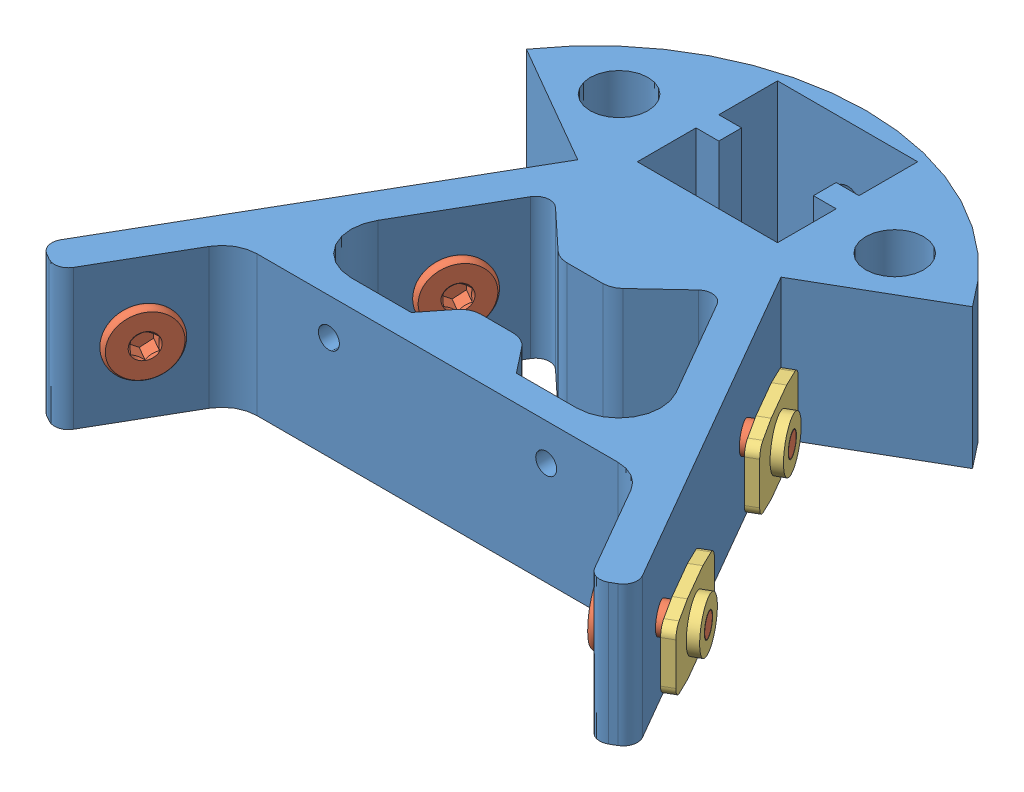
SolidWorks assembly Lower Vertex, configuration Default. Lengths in mm.
Overall size (92.08 20 77.1).
13 component instances, 3 part files, 12 mates.
Components (placement in the parent):
- Vertex-6: Vertex [Lower Vertex] at (68.2109 50.6126 50.9383) size (83.54 20 76.93)
- M4_Low_Profile_Screw_with_T_nut-1: M4_Low_Profile_Screw_with_T_nut [M4-10mm] at (106.8847 59.4609 67.0612) x (0.866025 0 -0.5) z (0.5 0 0.866025) size (11.62 10 15)
  - Low Profile Screw M4-1: Low Profile Screw M4 [M5 x 10] at (4.1063 1.1517 0.1173) size (11.62 9 9)
  - Tee Nut M4-1: Tee Nut M4 [Default] at (1.1063 1.1517 0.1173) x (0 0 -1) z (1 0 0) size (15 10 3)
- M4_Low_Profile_Screw_with_T_nut-2: M4_Low_Profile_Screw_with_T_nut [M4-10mm] at (29.4198 59.4609 67.2644) x (-0.866025 0 -0.5) z (0.5 0 -0.866025) size (11.62 10 15)
  - Low Profile Screw M4-1: Low Profile Screw M4 [M5 x 10] at (4.1063 1.1517 0.1173) size (11.62 9 9)
  - Tee Nut M4-1: Tee Nut M4 [Default] at (1.1063 1.1517 0.1173) x (0 0 -1) z (1 0 0) size (15 10 3)
- M4_Low_Profile_Screw_with_T_nut-3: M4_Low_Profile_Screw_with_T_nut [M4-10mm] at (45.7554 59.4609 38.9703) x (-0.866025 0 -0.5) z (0.5 0 -0.866025) size (11.62 10 15)
  - Low Profile Screw M4-1: Low Profile Screw M4 [M5 x 10] at (4.1063 1.1517 0.1173) size (11.62 9 9)
  - Tee Nut M4-1: Tee Nut M4 [Default] at (1.1063 1.1517 0.1173) x (0 0 -1) z (1 0 0) size (15 10 3)
- M4_Low_Profile_Screw_with_T_nut-4: M4_Low_Profile_Screw_with_T_nut [M4-10mm] at (90.5491 59.4609 38.7671) x (0.866025 0 -0.5) z (0.5 0 0.866025) size (11.62 10 15)
  - Low Profile Screw M4-1: Low Profile Screw M4 [M5 x 10] at (4.1063 1.1517 0.1173) size (11.62 9 9)
  - Tee Nut M4-1: Tee Nut M4 [Default] at (1.1063 1.1517 0.1173) x (0 0 -1) z (1 0 0) size (15 10 3)
Mates (geometry in assembly coordinates):
- Concentric11: concentric anti-aligned: cylinder of Vertex-6 through (101.8393 60.6126 70.1097) axis (-0.866025 0 0.5) radius 2; cylinder of M4_Low_Profile_Screw_with_T_nut-1/Low Profile Screw M4-1 through (101.8393 60.6126 70.1097) axis (0.866025 0 -0.5) radius 2
- Coincident11: coincident anti-aligned: plane of Vertex-6 through (96.8545 70.6126 61.4757) normal (-0.866025 0 0.5); plane of M4_Low_Profile_Screw_with_T_nut-1/Low Profile Screw M4-1 through (101.8393 64.774 70.1097) normal (0.866025 0 -0.5)
- Concentric21: concentric anti-aligned: cylinder of Vertex-6 through (34.5825 60.6126 70.1097) axis (0.866025 0 0.5) radius 2; cylinder of M4_Low_Profile_Screw_with_T_nut-2/Low Profile Screw M4-1 through (34.5825 60.6126 70.1097) axis (-0.866025 0 -0.5) radius 2
- Coincident21: coincident anti-aligned: plane of Vertex-6 through (39.5673 70.6126 61.4757) normal (0.866025 0 0.5); plane of M4_Low_Profile_Screw_with_T_nut-2/Low Profile Screw M4-1 through (34.5825 64.774 70.1097) normal (-0.866025 0 -0.5)
- Concentric31: concentric anti-aligned: cylinder of Vertex-6 through (50.9181 60.6126 41.8155) axis (0.866025 0 0.5) radius 2; cylinder of M4_Low_Profile_Screw_with_T_nut-3/Low Profile Screw M4-1 through (50.9181 60.6126 41.8155) axis (-0.866025 0 -0.5) radius 2
- Coincident31: coincident anti-aligned: plane of Vertex-6 through (56.1661 70.6126 32.7257) normal (0.866025 0 0.5); plane of M4_Low_Profile_Screw_with_T_nut-3/Low Profile Screw M4-1 through (50.9181 64.774 41.8155) normal (-0.866025 0 -0.5)
- Concentric41: concentric anti-aligned: cylinder of Vertex-6 through (85.5037 60.6126 41.8155) axis (-0.866025 0 0.5) radius 2; cylinder of M4_Low_Profile_Screw_with_T_nut-4/Low Profile Screw M4-1 through (85.5037 60.6126 41.8155) axis (0.866025 0 -0.5) radius 2
- Coincident41: coincident anti-aligned: plane of Vertex-6 through (94.6894 70.6126 57.7257) normal (-0.866025 0 0.5); plane of M4_Low_Profile_Screw_with_T_nut-4/Low Profile Screw M4-1 through (85.5037 64.774 41.8155) normal (0.866025 0 -0.5)
- Parallel1: parallel aligned: plane of Vertex-6 through (68.2109 70.6126 39.0329) normal (0 1 0); plane of M4_Low_Profile_Screw_with_T_nut-3/Tee Nut M4-1 through (44.9703 65.6126 34.9174) normal (0 1 0)
- Parallel2: parallel aligned: plane of Vertex-6 through (68.2109 70.6126 39.0329) normal (0 1 0); plane of M4_Low_Profile_Screw_with_T_nut-2/Tee Nut M4-1 through (28.6347 65.6126 63.2116) normal (0 1 0)
- Parallel3: parallel aligned: plane of Vertex-6 through (68.2109 70.6126 39.0329) normal (0 1 0); plane of M4_Low_Profile_Screw_with_T_nut-4/Tee Nut M4-1 through (94.4515 65.6126 40.1136) normal (0 1 0)
- Parallel4: parallel aligned: plane of Vertex-6 through (68.2109 70.6126 39.0329) normal (0 1 0); plane of M4_Low_Profile_Screw_with_T_nut-1/Tee Nut M4-1 through (110.7871 65.6126 68.4077) normal (0 1 0)
